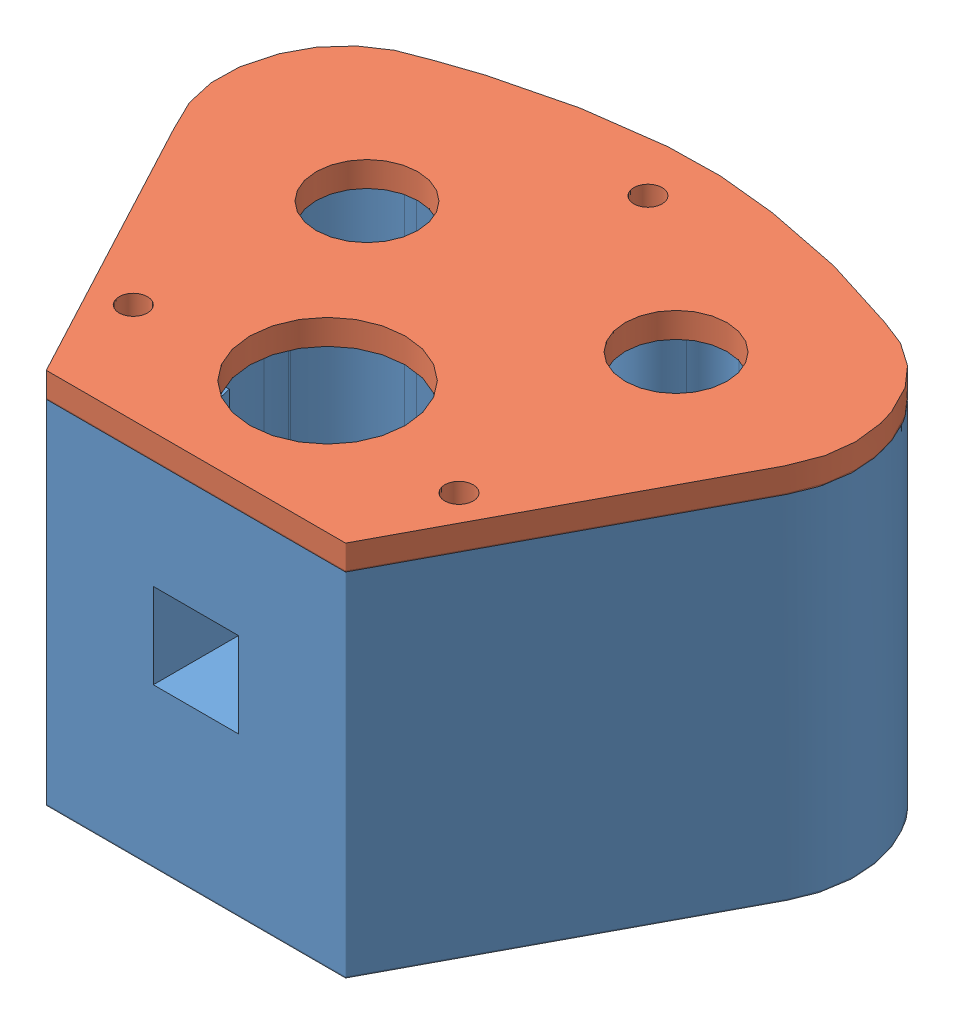
SolidWorks assembly Assem1, configuration По умолчанию. Lengths in mm.
Overall size (76.19 45.1 60.74).
2 component instances, 2 part files, 3 mates.
Components (placement in the parent):
- 206h_sw_box_206h01-1: 206h_sw_box_206h01 [По умолчанию] at origin size (76.19 42.1 60.73)
- 206h_sw_box_cover_206h02-1: 206h_sw_box_cover_206h02 [По умолчанию] at (0 42.1 0) size (76.19 3 60.74)
Mates (geometry in assembly coordinates):
- Concentric1: concentric aligned: cylinder of 206h_sw_box_206h01-1 through (-19.5 0.1 27.6096) axis (0 -1 0) radius 1.7; cylinder of 206h_sw_box_cover_206h02-1 through (-19.5 42.2 27.6096) axis (0 -1 0) radius 1.7
- Concentric2: concentric aligned: cylinder of 206h_sw_box_206h01-1 through (19.5 0.1 27.6096) axis (0 -1 0) radius 1.7; cylinder of 206h_sw_box_cover_206h02-1 through (19.5 42.2 27.6096) axis (0 -1 0) radius 1.7
- Coincident1: coincident anti-aligned: plane of 206h_sw_box_206h01-1 through (-22.492 42.1 31.0272) normal (0 1 0); plane of 206h_sw_box_cover_206h02-1 through (21.6267 42.1 -1.0743) normal (0 -1 0)
